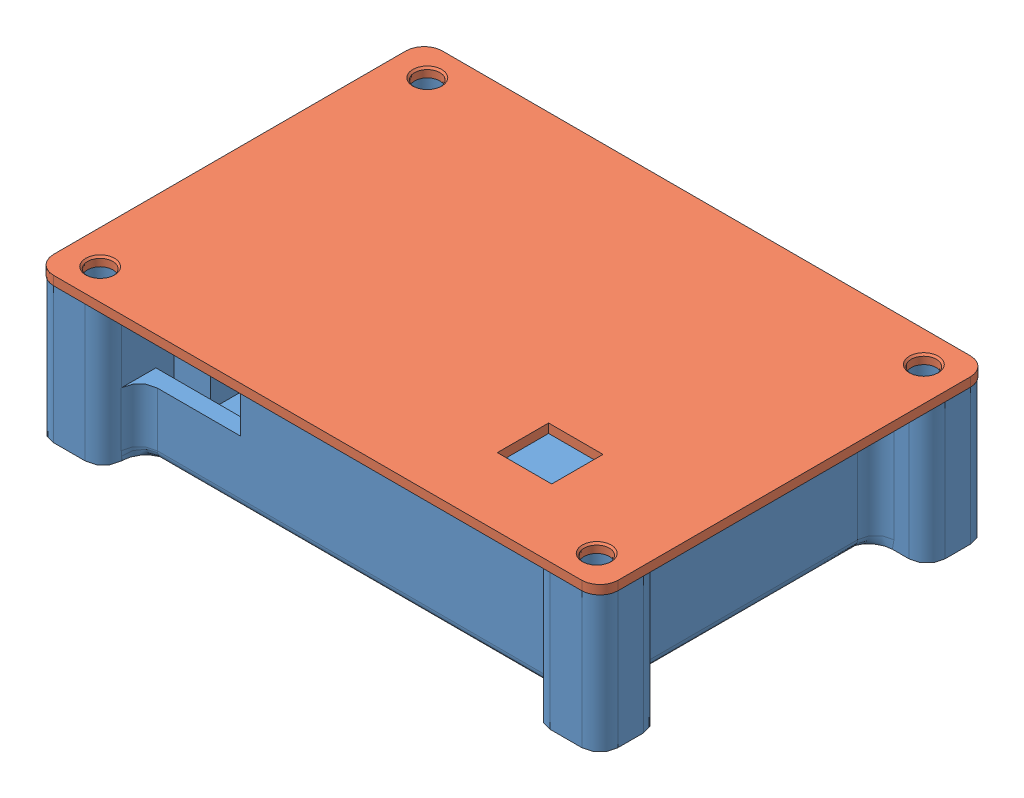
SolidWorks assembly złożenie-obudowy, configuration Domyślna. Lengths in mm.
Overall size (62.3 16 42.9).
2 component instances, 2 part files, 3 mates.
Components (placement in the parent):
- obudowa — kopia-1: obudowa — kopia [Domyślna] at origin size (62.3 15 42.9)
- obudowa - pokrywa-1: obudowa - pokrywa [Domyślna] at (-0.0002 10 0.0001) x (1 0 -0.000009) z (0.000009 0 1) size (62.3 1 42.9)
Mates (geometry in assembly coordinates):
- Wspólnie1: coincident anti-aligned: plane of obudowa — kopia-1 through (0 10 0) normal (0 1 0); plane of obudowa - pokrywa-1 through (-0.0002 10 0.0001) normal (0 -1 0)
- Koncentryczne1: concentric aligned: cylinder of obudowa — kopia-1 through (-27.4 -15.1237 18.0503) axis (0 1 0) radius 1.81; cylinder of obudowa - pokrywa-1 through (-27.4 1 18.0503) axis (0 1 0) radius 1.4
- Koncentryczne2: concentric aligned: cylinder of obudowa — kopia-1 through (27.4 -15.1237 -18.0503) axis (0 1 0) radius 1.81; cylinder of obudowa - pokrywa-1 through (27.3997 1 -18.0501) axis (0 1 0) radius 1.4
